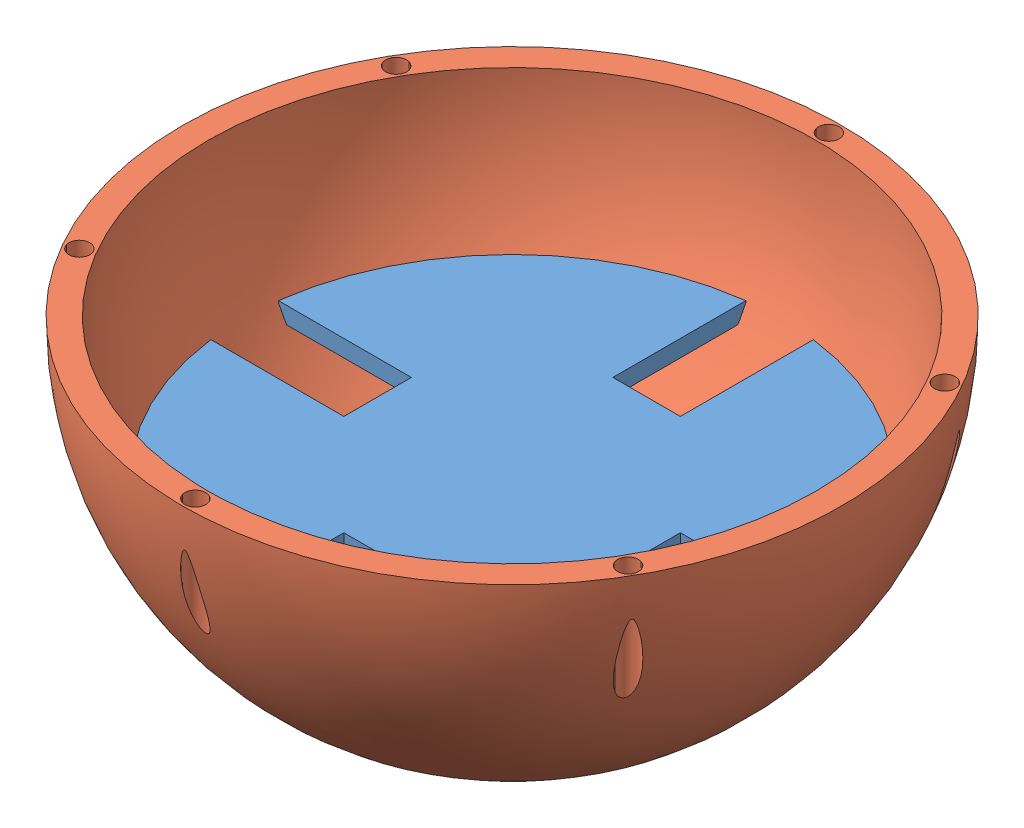
SolidWorks assembly Assem1, configuration Default. Lengths in mm.
Overall size (247.9 123.95 247.9).
2 component instances, 2 part files, 1 mates.
Components (placement in the parent):
- MidWood Base-1: MidWood Base [Default] at (46.2993 163.7727 108.6653) size (201.15 6.35 201.15)
- BB-8 Body Shell V2-2: BB-8 Body Shell V2 [Default] at (46.2993 221.8679 108.6653) size (247.9 123.95 247.9)
Mates (geometry in assembly coordinates):
- Concentric3: concentric aligned: circle of MidWood Base-1; circle of BB-8 Body Shell V2-2
